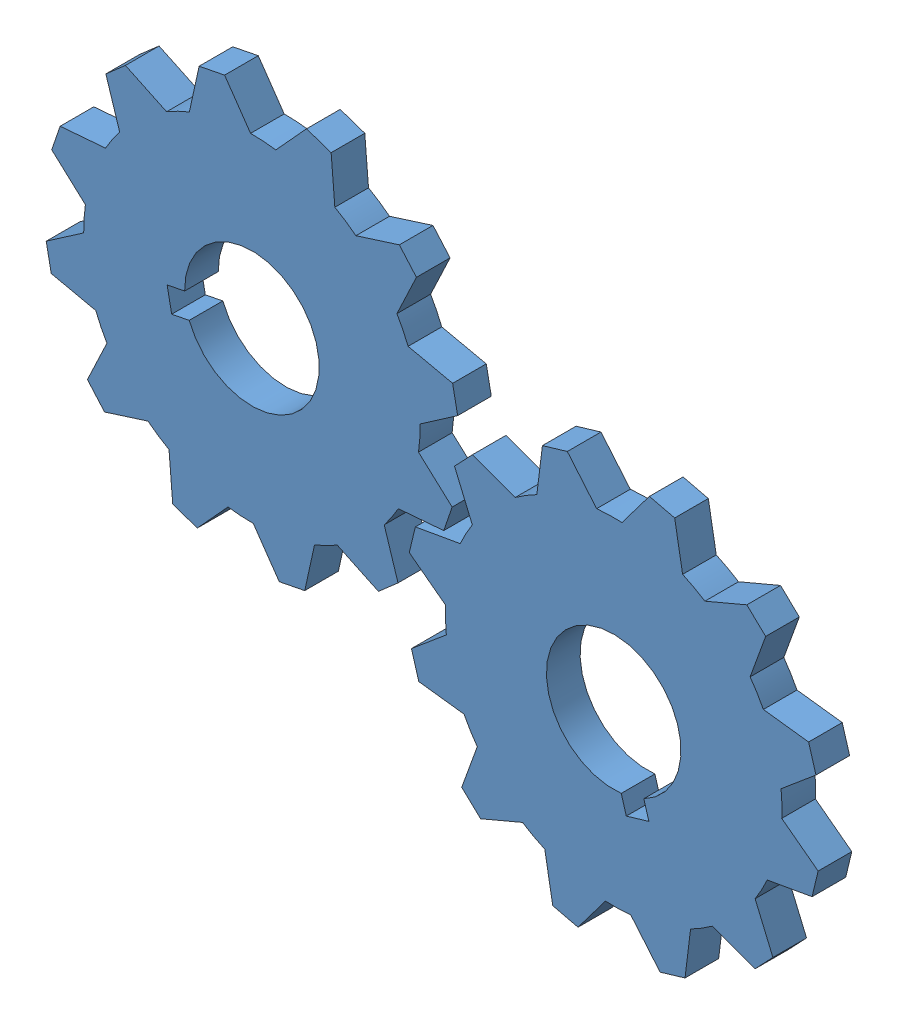
SolidWorks assembly Test_5_2_Working, configuration Default. Lengths in mm.
Overall size (256.31 193.71 10).
3 component instances, 2 part files, 7 mates.
Components (placement in the parent):
- Gear_2-3: Gear_2 [Default] at (-105.6577 26.5914 -10) x (0.958794 0.284101 0) z (0 0 1) size (123.1 123.1 10)
- Gear_2-4: Gear_2 [Default] at (-213.1724 71.5073 -10) x (0.193443 -0.981111 0) z (0 0 1) size (123.1 123.1 10)
- Background-1: Background [Default] at (-164.4985 122.0365 0) size (280 220 10) (hidden)
Mates (geometry in assembly coordinates):
- Concentric1: concentric anti-aligned: circle of Gear_1-4
- Concentric2: concentric anti-aligned: circle of Gear_1-3
- Coincident3: coincident anti-aligned: plane of Background-1 through (-164.4985 122.0365 0) normal (0 0 -1)
- Coincident4: coincident aligned: plane of Background-1 through (0 220 10) normal (1 0 0)
- Coincident5: coincident anti-aligned: plane of Background-1 through (-280 0 10) normal (0 -1 0)
- Coincident6: coincident anti-aligned: plane of Gear_1-4 through (-213.1724 71.5073 0) normal (0 0 1); plane of Background-1 through (-164.4985 122.0365 0) normal (0 0 -1)
- Coincident7: coincident anti-aligned: plane of Gear_1-3 through (-105.6577 26.5914 0) normal (0 0 1); plane of Background-1 through (-164.4985 122.0365 0) normal (0 0 -1)
